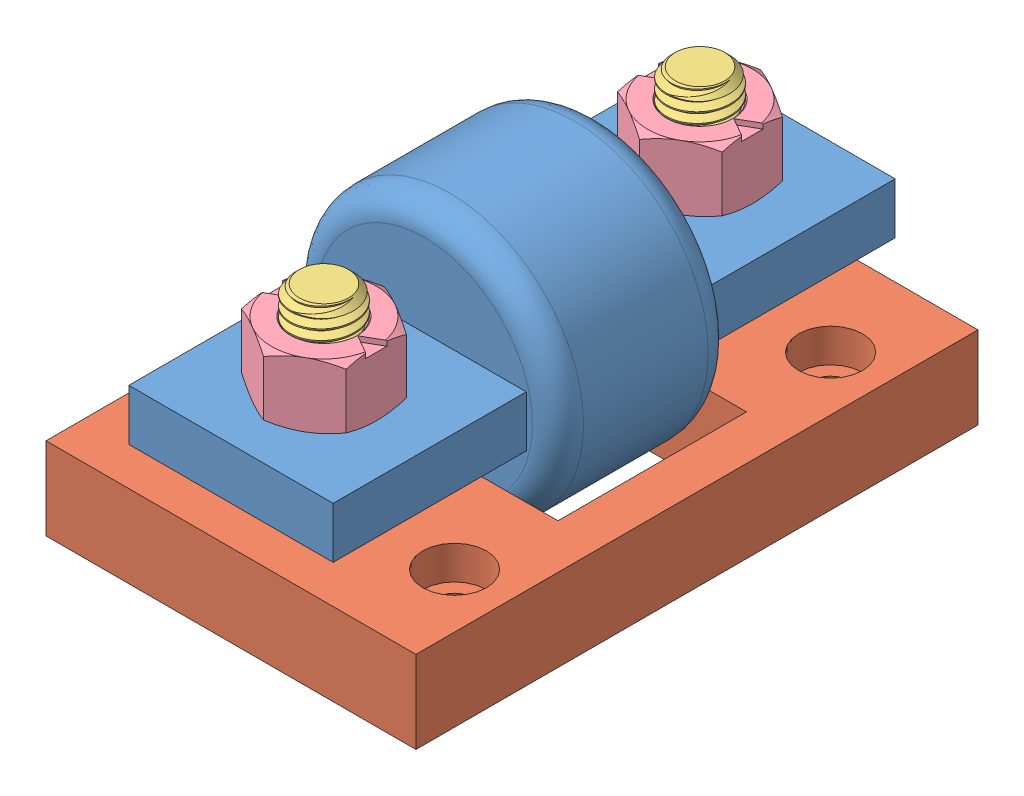
SolidWorks assembly Fuse Holder, configuration Default. Lengths in mm.
Overall size (45.97 34.81 69.85).
6 component instances, 4 part files, 14 mates.
Components (placement in the parent):
- 350A Fuse-1: 350A Fuse [Default] at (0 18.1747 -10.922) size (33.27 33.27 69.85)
- Part1^Fuse Holder-1: Part1^Fuse Holder [Default] at origin size (45.97 10.24 69.85) (virtual)
- 91287A153_18-8 STAINLESS STEEL HEX HEAD CAP SCREW-3: 91287A153_18-8 STAINLESS STEEL HEX HEAD CAP SCREW [91287A153] at (0 17.7059 23.368) x (0 1 0) z (0 0 1) size (30.8 15.01 13)
- 91287A153_18-8 STAINLESS STEEL HEX HEAD CAP SCREW-2: 91287A153_18-8 STAINLESS STEEL HEX HEAD CAP SCREW [91287A153] at (0 17.7059 -23.368) x (0 1 0) z (0 0 1) size (30.8 15.01 13)
- 93795A230_CLASS 8 STEEL DISTORTED-THREAD TOPLOCK NUT-1: 93795A230_CLASS 8 STEEL DISTORTED-THREAD TOPLOCK NUT [93795A230] at (0 21.3497 -23.368) x (1 0 0) z (0 1 0) size (13 15.01 8.6)
- 93795A230_CLASS 8 STEEL DISTORTED-THREAD TOPLOCK NUT-2: 93795A230_CLASS 8 STEEL DISTORTED-THREAD TOPLOCK NUT [93795A230] at (0 21.3497 23.368) x (1 0 0) z (0 1 0) size (13 15.01 8.6)
Mates (geometry in assembly coordinates):
- Symmetric2: symmetric: plane of 350A Fuse-1 through (0 18.1747 34.925) normal (0 0 1); plane of 350A Fuse-1 through (0 18.1747 -34.925) normal (0 0 -1); plane of assembly
- Symmetric3: symmetric: plane of 350A Fuse-1 through (12.7 14.9997 -34.925) normal (1 0 0); plane of 350A Fuse-1 through (-12.7 14.9997 -34.925) normal (-1 0 0); plane of assembly
- Distance2: distance = 2.3813 mm: plane of 91287A153_18-8 STAINLESS STEEL HEX HEAD CAP SCREW-3 through (3.7528 7.8559 16.868) normal (0 1 0); plane of Part1^Fuse Holder-1 through (-12.7 10.2372 -34.925) normal (0 1 0)
- Concentric1: concentric: cylinder of 350A Fuse-1 through (0 1.5377 23.368) axis (0 1 0) radius 4.7625; cylinder of 91287A153_18-8 STAINLESS STEEL HEX HEAD CAP SCREW-3 through (0 7.8559 23.368) axis (0 1 0) radius 4
- Concentric2: concentric: cylinder of 350A Fuse-1 through (0 1.5377 -23.368) axis (0 1 0) radius 4.7625; cylinder of 91287A153_18-8 STAINLESS STEEL HEX HEAD CAP SCREW-2 through (0 7.8559 -23.368) axis (0 1 0) radius 4
- Parallel1: parallel: plane of 91287A153_18-8 STAINLESS STEEL HEX HEAD CAP SCREW-3 through (0 17.7059 23.368) normal (0 0 1); plane of assembly through (0 0 0) normal (0 0 1)
- Parallel2: parallel: plane of 91287A153_18-8 STAINLESS STEEL HEX HEAD CAP SCREW-2 through (0 17.7059 -23.368) normal (0 0 1); plane of assembly through (0 0 0) normal (0 0 1)
- Coincident6: coincident: plane of 350A Fuse-1 through (-12.7 21.3497 -34.925) normal (0 1 0); plane of 93795A230_CLASS 8 STEEL DISTORTED-THREAD TOPLOCK NUT-1 through (-6.5 21.3497 -34.6263) normal (0 -1 0)
- Concentric3: concentric: cylinder of 91287A153_18-8 STAINLESS STEEL HEX HEAD CAP SCREW-2 through (0 7.8559 -23.368) axis (0 1 0) radius 4; cylinder of 93795A230_CLASS 8 STEEL DISTORTED-THREAD TOPLOCK NUT-1 through (0 29.3497 -23.368) axis (0 -1 0) radius 3.3234
- Parallel4: parallel: plane of 93795A230_CLASS 8 STEEL DISTORTED-THREAD TOPLOCK NUT-1 through (0 21.3497 -23.368) normal (0 0 -1); plane of assembly through (0 0 0) normal (0 0 1)
- Coincident7: coincident: plane of 350A Fuse-1 through (-12.7 21.3497 34.925) normal (0 1 0); plane of 93795A230_CLASS 8 STEEL DISTORTED-THREAD TOPLOCK NUT-2 through (-6.5 21.3497 12.1097) normal (0 -1 0)
- Concentric4: concentric: cylinder of 91287A153_18-8 STAINLESS STEEL HEX HEAD CAP SCREW-3 through (0 7.8559 23.368) axis (0 1 0) radius 4; cylinder of 93795A230_CLASS 8 STEEL DISTORTED-THREAD TOPLOCK NUT-2 through (0 29.3497 23.368) axis (0 -1 0) radius 3.3234
- Parallel5: parallel: plane of 93795A230_CLASS 8 STEEL DISTORTED-THREAD TOPLOCK NUT-2 through (0 21.3497 23.368) normal (0 0 -1); plane of assembly through (0 0 0) normal (0 0 1)
- Coincident8: coincident: plane of 91287A153_18-8 STAINLESS STEEL HEX HEAD CAP SCREW-3 through (3.7528 7.8559 16.868) normal (0 1 0); plane of 91287A153_18-8 STAINLESS STEEL HEX HEAD CAP SCREW-2 through (3.7528 7.8559 -29.868) normal (0 1 0)
